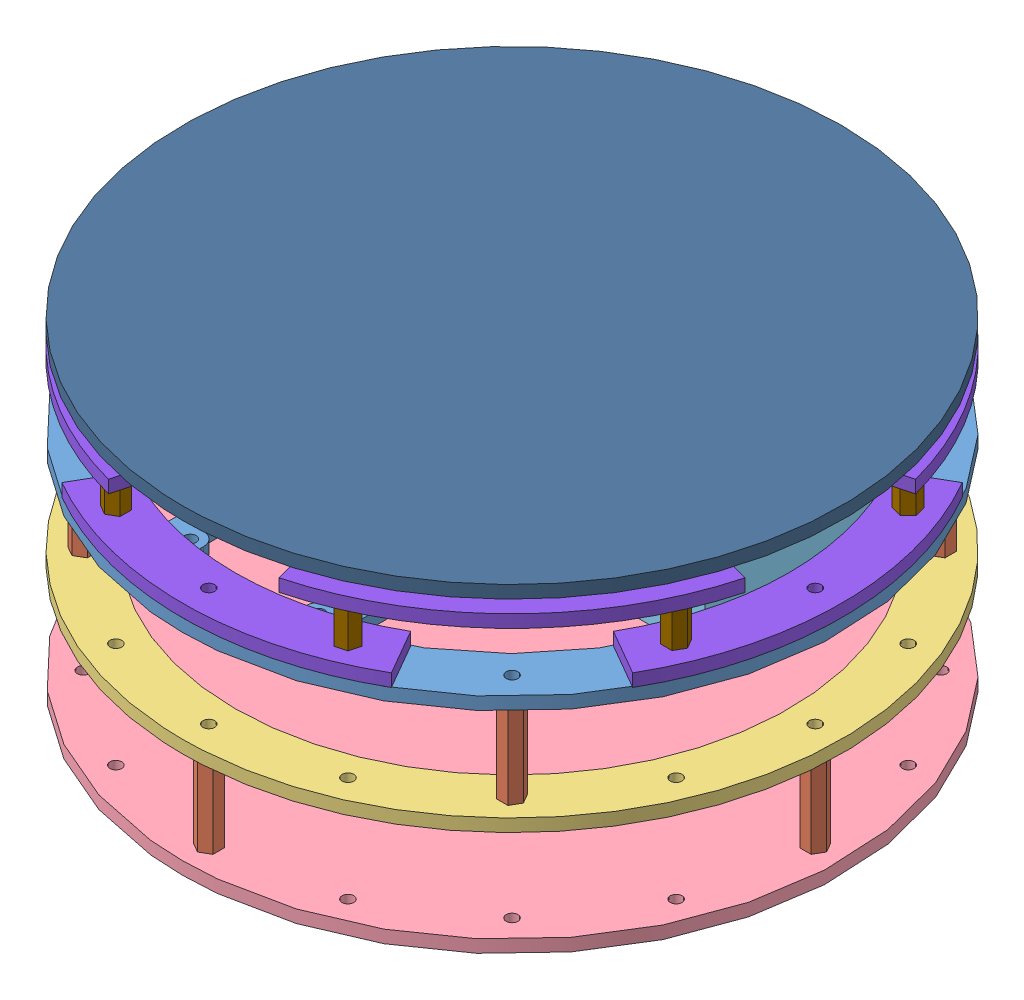
SolidWorks assembly TurnTable, configuration Default. Lengths in mm.
Overall size (216.86 77.06 216.86).
33 component instances, 11 part files, 15 mates.
Components (placement in the parent):
- HousingSteppeMotor-1: HousingSteppeMotor [Default] at (5.6062 7.9908 1.9149) size (158.75 74.02 158.75)
  - Base Unit-1: Base Unit [Default] at (-15.6008 25.016 -9.7985) size (158.75 3.05 158.75)
  - Part11^HousingSteppeMotor-1: Part11^HousingSteppeMotor [Default] at origin (virtual)
  - LHexStandoff-1: LHexStandoff [Default] at (-18.4264 2.7402 134.3541) x (0.866025 0 -0.5) z (0 1 0) size (5.46 4.72 22.28)
  - LHexStandoff-2: LHexStandoff [Default] at (128.5518 2.7402 -6.9729) x (-0.5 0 -0.866025) z (0 1 0) size (5.46 4.72 22.28)
  - LHexStandoff-3: LHexStandoff [Default] at (-12.7752 2.7402 -153.9512) x (-0.866025 0 0.5) z (0 1 0) size (5.46 4.72 22.28)
  - LHexStandoff-4: LHexStandoff [Default] at (-159.7534 2.7402 -12.6242) x (0.5 0 0.866025) z (0 1 0) size (5.46 4.72 22.28)
  - Generic Unit-1: Generic Unit [Default] at (-15.6008 -0.3078 -9.7985) size (158.75 3.05 158.75)
  - LHexStandoff-5: LHexStandoff [Default] at (33.21 -22.5836 9.6926) x (0.866025 0 -0.5) z (0 1 0) size (5.46 4.72 22.28)
  - LHexStandoff-6: LHexStandoff [Default] at (3.8904 -22.5836 -58.6094) x (-0.5 0 -0.866025) z (0 1 0) size (5.46 4.72 22.28)
  - LHexStandoff-7: LHexStandoff [Default] at (-64.4116 -22.5836 -29.2897) x (-0.866025 0 0.5) z (0 1 0) size (5.46 4.72 22.28)
  - LHexStandoff-8: LHexStandoff [Default] at (-35.092 -22.5836 39.0123) x (0.5 0 0.866025) z (0 1 0) size (5.46 4.72 22.28)
  - Bottom Panel-1: Bottom Panel [Default] at (-15.6008 -25.6316 -9.7985) size (158.75 3.05 158.75)
  - Stepper mock uo-1: Stepper mock uo [Default] at (-15.5754 1.521 -56.2559) x (1 0 0) z (0 1 0) size (42.01 42.01 70.36)
- Spur Gear_AI-1: Spur Gear_AI [Inch - Spur gear 24DP 35T 20PA .12FW ---S35N3.0H2.0L0.25N] at (-9.9692 56.3748 -54.341) x (0 -1 0) z (0.488081 0 0.872799) size (3.05 39.11 39.14)
- Internal Spur Gear_AI-1: Internal Spur Gear_AI [Inch - Internal spur gear 24DP 123T 20PA .12FW ---S123S5.5OD 1.0AF] at (-9.9946 56.3748 -7.8836) x (0 -1 0) z (0.983326 0 -0.181852) size (3.05 139.7 139.7)
- extention-1: extention [Default] at (-9.9946 36.0548 -7.8836) x (0.707107 0 -0.707107) z (0.707107 0 0.707107) size (59.41 3.05 59.41)
- extention-2: extention [Default] at (-9.9946 36.0548 -7.8836) x (-0.707107 0 -0.707107) z (0.707107 0 -0.707107) size (59.41 3.05 59.41)
- extention-3: extention [Default] at (-9.9946 36.0548 -7.8836) x (-0.707107 0 0.707107) z (-0.707107 0 -0.707107) size (59.41 3.05 59.41)
- extention-4: extention [Default] at (-9.9946 36.0548 -7.8836) x (0.707107 0 0.707107) z (-0.707107 0 0.707107) size (59.41 3.05 59.41)
- SHexStandoff-2: SHexStandoff [Default] at (-19.1713 50.2788 -145.396) x (0.707107 0 -0.707107) z (0 -1 0) size (4.71 5.44 11.18)
- SHexStandoff-3: SHexStandoff [Default] at (-113.7194 50.2788 -98.6307) x (0 0 -1) z (0 -1 0) size (4.71 5.44 11.18)
- SHexStandoff-4: SHexStandoff [Default] at (-147.5069 50.2788 1.293) x (-0.707107 0 -0.707107) z (0 -1 0) size (4.71 5.44 11.18)
- SHexStandoff-5: SHexStandoff [Default] at (-100.7416 50.2788 95.8412) x (-1 0 0) z (0 -1 0) size (4.71 5.44 11.18)
- SHexStandoff-6: SHexStandoff [Default] at (-0.8179 50.2788 129.6287) x (-0.707107 0 0.707107) z (0 -1 0) size (4.71 5.44 11.18)
- SHexStandoff-7: SHexStandoff [Default] at (93.7302 50.2788 82.8634) x (0 0 1) z (0 -1 0) size (4.71 5.44 11.18)
- SHexStandoff-8: SHexStandoff [Default] at (127.5178 50.2788 -17.0603) x (0.707107 0 0.707107) z (0 -1 0) size (4.71 5.44 11.18)
- SHexStandoff-9: SHexStandoff [Default] at (80.7524 50.2788 -111.6084) x (1 0 0) z (0 -1 0) size (4.71 5.44 11.18)
- extention-5: extention [Default] at (-9.9946 50.2788 -7.8836) x (0 0 -1) z (1 0 0) size (59.41 3.05 59.41)
- extention-6: extention [Default] at (-9.9946 50.2788 -7.8836) x (-1 0 0) z (0 0 -1) size (59.41 3.05 59.41)
- extention-7: extention [Default] at (-9.9946 50.2788 -7.8836) x (0 0 1) z (-1 0 0) size (59.41 3.05 59.41)
- extention-8: extention [Default] at (-9.9946 50.2788 -7.8836) size (59.41 3.05 59.41)
- TurntablePlate-1: TurntablePlate [Default] at (-9.9946 56.3748 -7.8836) size (158.75 3.05 158.75)
Mates (geometry in assembly coordinates):
- Concentric1: concentric anti-aligned: cylinder of HousingSteppeMotor-1/Stepper mock uo-1 through (-9.9692 56.3748 -54.341) axis (0 -1 0) radius 2.54; cylinder of Spur Gear_AI-1 through (-9.9692 5.5747 -54.341) axis (0 1 0) radius 3.175
- Coincident1: coincident aligned: plane of HousingSteppeMotor-1/Stepper mock uo-1 through (-9.9692 56.3748 -54.341) normal (0 1 0); plane of Spur Gear_AI-1 through (-9.9692 56.3748 -54.341) normal (0 1 0)
- Concentric2: concentric anti-aligned: cylinder of HousingSteppeMotor-1/Base Unit-1 through (-9.9946 36.0548 -7.8836) axis (0 -1 0) radius 79.375; cylinder of Internal Spur Gear_AI-1 through (-9.9946 66.3748 -7.8836) axis (0 1 0) radius 69.85
- Coincident2: coincident aligned: plane of Spur Gear_AI-1 through (-9.9692 56.3748 -54.341) normal (0 1 0); plane of Internal Spur Gear_AI-1 through (-72.9561 56.3748 3.7602) normal (0 1 0)
- GearMate1: gear = 123 mm: cylinder of Spur Gear_AI-1 through (-9.9692 5.5747 -54.341) axis (0 1 0) radius 3.175; cylinder of Internal Spur Gear_AI-1 through (-9.9946 66.3748 -7.8836) axis (0 1 0) radius 69.85
- Coincident5: coincident aligned: circle of HousingSteppeMotor-1/Base Unit-1; circle of extention-1
- Coincident6: coincident aligned: circle of HousingSteppeMotor-1/Base Unit-1; circle of extention-1
- Concentric5: concentric anti-aligned: cylinder of extention-1 through (-37.94 39.1028 -75.3499) axis (0 -1 0) radius 1.4224; cylinder of SHexStandoff-2 through (-37.94 39.1028 -75.3499) axis (0 1 0) radius 1.397
- Coincident7: coincident anti-aligned: plane of extention-1 through (-9.9946 39.1028 -7.8836) normal (0 1 0); plane of SHexStandoff-2 through (-19.1713 39.1028 -145.396) normal (0 -1 0)
- Parallel1: parallel anti-aligned: plane of SHexStandoff-9 through (15.595 39.1028 -73.9898) normal (-1 0 0); plane of assembly through (0 0 0) normal (1 0 0)
- Concentric7: concentric anti-aligned: cylinder of SHexStandoff-3 through (-77.4609 39.1028 -35.8291) axis (0 1 0) radius 1.397; cylinder of extention-5 through (-77.4609 53.3268 -35.8291) axis (0 -1 0) radius 1.4224
- Coincident10: coincident anti-aligned: plane of SHexStandoff-3 through (-113.7194 50.2788 -98.6307) normal (0 1 0); plane of extention-5 through (-9.9946 50.2788 -7.8836) normal (0 -1 0)
- Concentric8: concentric anti-aligned: cylinder of SHexStandoff-2 through (-37.94 39.1028 -75.3499) axis (0 1 0) radius 1.397; cylinder of extention-5 through (-37.94 53.3268 -75.3499) axis (0 -1 0) radius 1.4224
- Coincident14: coincident anti-aligned: plane of Internal Spur Gear_AI-1 through (-72.9561 56.3748 3.7602) normal (0 1 0); plane of TurntablePlate-1 through (-9.9946 56.3748 -7.8836) normal (0 -1 0)
- Concentric9: concentric anti-aligned: cylinder of Internal Spur Gear_AI-1 through (-9.9946 66.3748 -7.8836) axis (0 1 0) radius 69.85; cylinder of TurntablePlate-1 through (-9.9946 59.4228 -7.8836) axis (0 -1 0) radius 79.375
